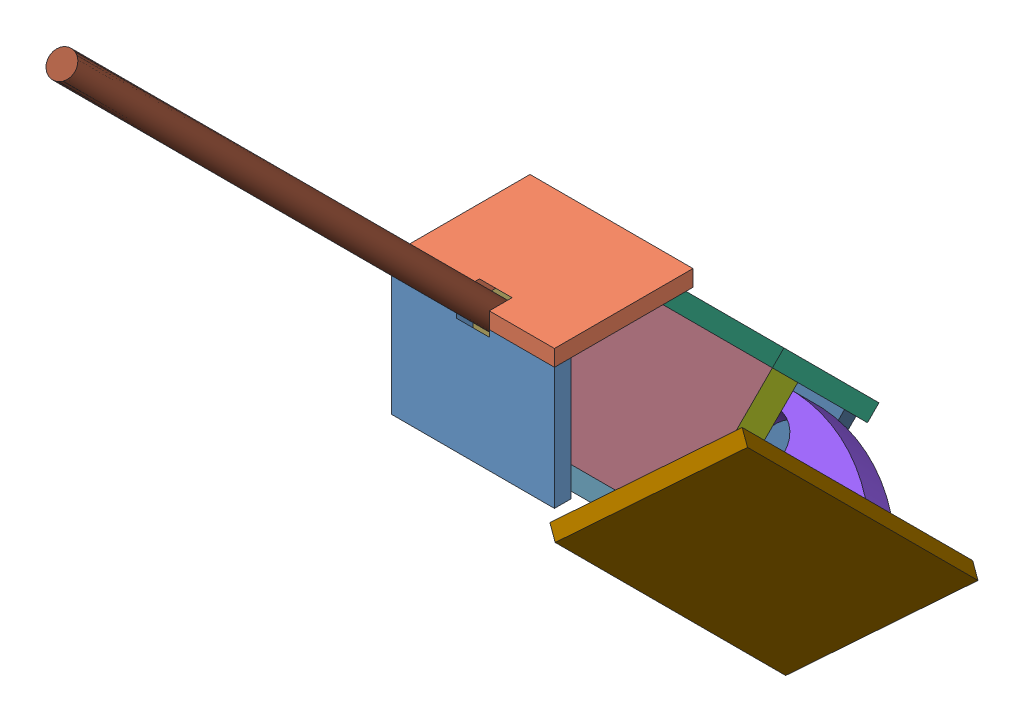
SolidWorks assembly AssemblaCabineDePlage(Violet), configuration Défaut. Lengths in mm.
Overall size (169.78 498.33 482.25).
11 component instances, 11 part files, 26 mates.
Components (placement in the parent):
- Pièce2-1: Pièce2 [Défaut] at (3.4185 -2.3604 95) size (100 75 10)
- Pièce3-vers2-1: Pièce3-vers2 [Défaut] at (3.4185 45.1396 62.5) x (1 0 0) z (0 -1 0) size (100 85 10)
- Pièce6-1: Pièce6 [Défaut] at (-36.5815 -0.2157 59.6447) x (0 -0.707107 0.707107) z (-1 0 0) size (80 100 10)
- Pièce7-1: Pièce7 [Défaut] at (43.4185 -20.9512 38.2695) x (0 0.707107 -0.707107) z (1 0 0) size (80 135 10)
- Pièce4-1: Pièce4 [Défaut] at (3.4185 -102.7462 27.8249) x (1 0 0) z (0 0.707107 -0.707107) size (100 210 10)
- Pièce5-1: Pièce5 [Défaut] at (3.4185 -39.1066 -35.8148) x (1 0 0) z (0 0.707107 -0.707107) size (100 210 10)
- Pièce12-1: Pièce12 [Défaut] at (3.4185 -83.3008 -8.5911) x (0 0.707107 -0.707107) z (0 0.707107 0.707107) size (112 100 22)
- Pièce10-5: Pièce10 [Défaut] at (89.5208 -90.5196 -1.3724) x (0.774566 -0.44724 0.44724) z (0 -0.707107 -0.707107) size (99 113.14 22)
- Pièce8-2: Pièce8 [Défaut] at (83.8284 -90.4991 8.5067) x (0.632493 0.547701 -0.547701) z (0.774566 -0.44724 0.44724) size (100 200 10)
- Pièce11-1: Pièce11 [Défaut] at (-11.5815 -141.6371 -81.7767) x (0 -0.707107 0.707107) z (0 0.707107 0.707107) size (80 70 10)
- Pièce1-1: Pièce1 [Défaut] at (3.4185 116.1987 176.0591) x (-0.583773 -0.574112 0.574112) z (-0.811917 0.41279 -0.41279) size (16 500 16)
Mates (geometry in assembly coordinates):
- Coïncidente1: coincident anti-aligned: plane of Pièce2-1 through (-46.5815 35.1396 105) normal (0 1 0); plane of Pièce3-vers2-1 through (3.4185 35.1396 62.5) normal (0 -1 0)
- Coïncidente2: coincident aligned: line of Pièce2-1 through (-46.5815 35.1396 105) axis (1 0 0); line of Pièce3-vers2-1 through (13.4185 35.1396 105) axis (1 0 0)
- Coïncidente3: coincident anti-aligned: line of Pièce2-1 through (53.4185 35.1396 105) axis (0 0 -1); line of Pièce3-vers2-1 through (53.4185 35.1396 20) axis (0 0 1)
- Coïncidente5: coincident anti-aligned: plane of Pièce3-vers2-1 through (3.4185 35.1396 62.5) normal (0 -1 0); plane of Pièce6-1 through (-46.5815 35.1396 38.4315) normal (0 1 0)
- Coïncidente6: coincident anti-aligned: plane of Pièce2-1 through (3.4185 -2.3604 95) normal (0 0 -1); plane of Pièce6-1 through (-46.5815 35.1396 95) normal (0 0 1)
- Coïncidente7: coincident aligned: line of Pièce2-1 through (-46.5815 -39.8604 95) axis (0 1 0); line of Pièce6-1 through (-46.5815 -21.4289 95) axis (0 1 0)
- Coïncidente8: coincident anti-aligned: plane of Pièce3-vers2-1 through (3.4185 35.1396 62.5) normal (0 -1 0); plane of Pièce7-1 through (53.4185 35.1396 95) normal (0 1 0)
- Coïncidente9: coincident anti-aligned: plane of Pièce2-1 through (3.4185 -2.3604 95) normal (0 0 -1); plane of Pièce7-1 through (53.4185 -21.4289 95) normal (0 0 1)
- Coïncidente10: coincident aligned: line of Pièce2-1 through (53.4185 -39.8604 95) axis (0 1 0); line of Pièce7-1 through (53.4185 -21.4289 95) axis (0 1 0)
- Coïncidente12: coincident anti-aligned: plane of Pièce2-1 through (3.4185 -2.3604 95) normal (0 0 -1); plane of Pièce4-1 through (-46.5815 -21.4289 95) normal (0 0 1)
- Coïncidente13: coincident anti-aligned: plane of Pièce7-1 through (53.4185 -88.6041 27.8249) normal (0 -0.707107 0.707107); plane of Pièce4-1 through (3.4185 -95.6751 20.7538) normal (0 0.707107 -0.707107)
- Coïncidente14: coincident anti-aligned: line of Pièce7-1 through (53.4185 -88.6041 27.8249) axis (0 0.707107 0.707107); line of Pièce4-1 through (53.4185 -21.4289 95) axis (0 -0.707107 -0.707107)
- Coïncidente15: coincident anti-aligned: plane of Pièce3-vers2-1 through (3.4185 35.1396 62.5) normal (0 -1 0); plane of Pièce5-1 through (-46.5815 35.1396 38.4315) normal (0 1 0)
- Coïncidente16: coincident anti-aligned: plane of Pièce6-1 through (-46.5815 -7.2868 -3.9949) normal (0 0.707107 -0.707107); plane of Pièce5-1 through (3.4185 -39.1066 -35.8148) normal (0 -0.707107 0.707107)
- Coïncidente17: coincident anti-aligned: line of Pièce7-1 through (53.4185 35.1396 38.4315) axis (0 -0.707107 -0.707107); line of Pièce5-1 through (53.4185 -32.0355 -28.7437) axis (0 0.707107 0.707107)
- Coïncidente25: coincident anti-aligned: plane of Pièce5-1 through (3.4185 -39.1066 -35.8148) normal (0 -0.707107 0.707107); plane of Pièce12-1 through (53.4185 -32.0355 -28.7437) normal (0 0.707107 -0.707107)
- Coïncidente37: coincident anti-aligned: plane of Pièce4-1 through (30.4185 -88.6041 27.8249) normal (0 -0.707107 -0.707107); plane of Pièce12-1 through (42.4185 -103.4533 42.6741) normal (0 0.707107 0.707107)
- Coïncidente41: coincident anti-aligned: circle of Pièce12-1; circle of Pièce10-5
- Coïncidente43: coincident aligned: line of Pièce7-1 through (53.4185 -88.6041 27.8249) axis (0 0.707107 -0.707107); line of Pièce12-1 through (53.4185 -103.4533 42.6741) axis (0 0.707107 -0.707107)
- Coïncidente45: coincident anti-aligned: plane of Pièce10-5 through (89.5208 -106.0759 -16.9287) normal (0.774566 -0.44724 0.44724); plane of Pièce8-2 through (83.8284 -90.4991 8.5067) normal (-0.774566 0.44724 -0.44724)
- Coïncidente46: coincident aligned: line of Pièce10-5 through (115.453 -83.6202 -39.3844) axis (0 0.707107 0.707107); line of Pièce8-2 through (115.453 -133.8248 -89.589) axis (0 0.707107 0.707107)
- Distance3: distance = 71 mm: line of Pièce10-5 through (115.453 -83.6202 -39.3844) axis (-0.632493 -0.547701 0.547701); line of Pièce8-2 through (52.2037 -188.5948 -34.8189) axis (0.632493 0.547701 -0.547701)
- Coïncidente55: coincident anti-aligned: plane of Pièce5-1 through (3.4185 -39.1066 -35.8148) normal (0 -0.707107 0.707107); plane of Pièce11-1 through (-46.5815 -106.2817 -102.9899) normal (0 0.707107 -0.707107)
- Coïncidente56: coincident aligned: line of Pièce5-1 through (-46.5815 -113.3528 -110.061) axis (1 0 0); line of Pièce11-1 through (-46.5815 -113.3528 -110.061) axis (1 0 0)
- Coïncidente57: coincident aligned: line of Pièce5-1 through (-46.5815 -106.2817 -117.132) axis (0 -0.707107 0.707107); line of Pièce11-1 through (-46.5815 -113.3528 -110.061) axis (0 -0.707107 0.707107)
- Coaxiale1: concentric anti-aligned: cylinder of Pièce12-1 through (3.4185 -60.3198 -0.4594) axis (0 -0.707107 -0.707107) radius 8; cylinder of Pièce1-1 through (3.4185 297.3636 357.224) axis (0 0.707107 0.707107) radius 8
